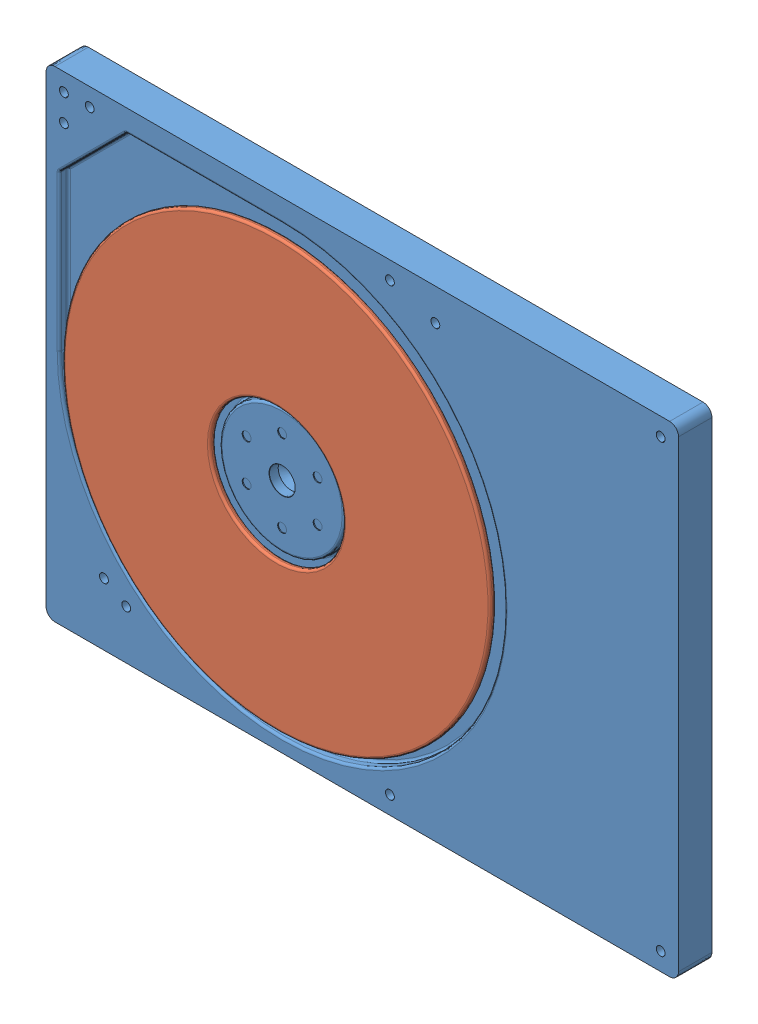
SolidWorks assembly HDD_1.8_Assem, configuration Default. Lengths in mm.
Overall size (71 54 4.39).
2 component instances, 2 part files, 2 mates.
Components (placement in the parent):
- HDD_1.8_Base-1: HDD_1.8_Base [Default] at origin size (71 54 3.75)
- HDD_1.8_Disk-1: HDD_1.8_Disk [Default] at (-9 -0.5 3.75) x (-1 0 0) z (0 0 1) size (48 48 0.64)
Mates (geometry in assembly coordinates):
- Concentric1: concentric anti-aligned: circle of HDD_1.8_Base-1; circle of HDD_1.8_Disk-1
- Distance1: distance = 1 mm anti-aligned: plane of HDD_1.8_Base-1 through (-9 -0.5 2.75) normal (0 0 1); plane of HDD_1.8_Disk-1 through (-9 -0.5 3.75) normal (0 0 -1)
